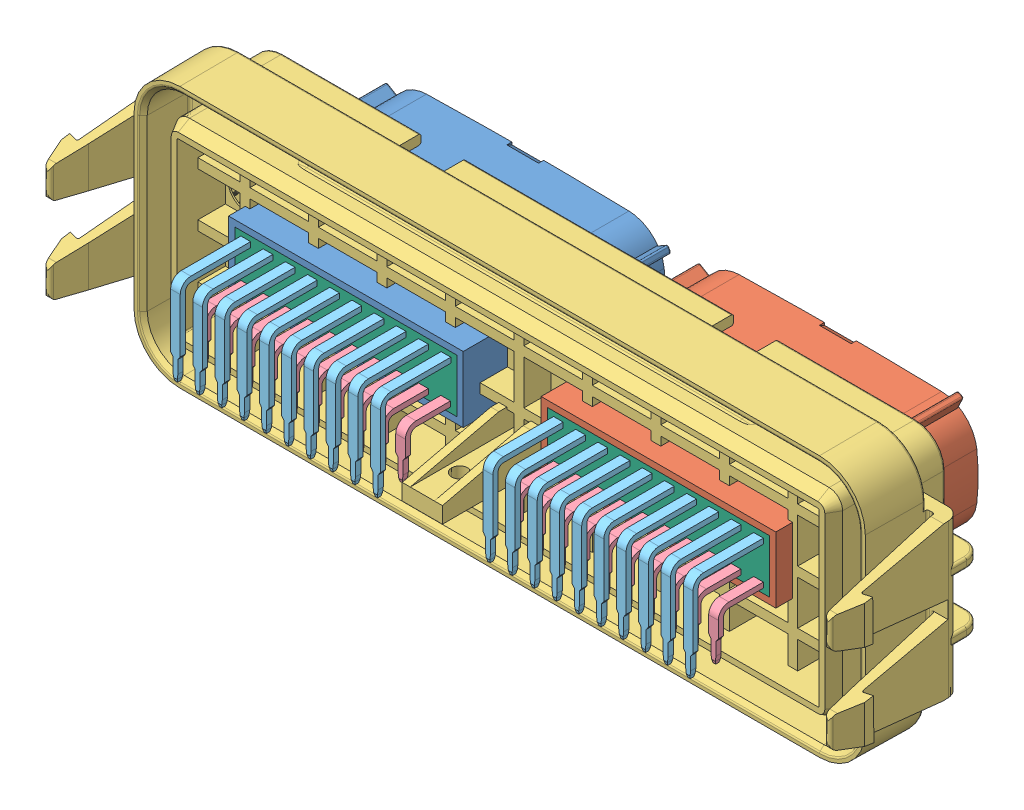
SolidWorks assembly 5810140011_model, configuration Default. Lengths in mm.
Overall size (126.6 41.34 41.26).
49 component instances, 6 part files, 0 mates.
Components (placement in the parent):
- 5810140011_model.stp-1: 5810140011_model.stp [Default] at origin size (126.6 41.34 41.26)
  - 4828770271-ME-MX-L20B-R20A_ASM.stp-1: 4828770271-ME-MX-L20B-R20A_ASM.stp [Default] at (0 -1.143 0) x (-1 0 0) z (0 0 -1) size (126.6 41.34 41.26)
    - MOLEX-ME-A-20W_AF2_ASM.stp-1: MOLEX-ME-A-20W_AF2_ASM.stp [Default] at (24.638 1.143 0) size (47 22 28.67)
      - MOLEX-ME-A-20W_AF3.stp-1: MOLEX-ME-A-20W_AF3.stp [Default] at (-17.9886 -11.4851 -14.215) size (47 22 28.67)
    - MOLEX-ME-B-20W_AF2_ASM.stp-1: MOLEX-ME-B-20W_AF2_ASM.stp [Default] at (-24.638 1.143 0) size (47 22 28.67)
      - MOLEX-ME-B-20W_AF3.stp-1: MOLEX-ME-B-20W_AF3.stp [Default] at (-17.9886 -11.4851 -14.215) size (47 22 28.67)
    - 4741170136_MX_ME_L20B-R20A_AF1.stp-1: 4741170136_MX_ME_L20B-R20A_AF1.stp [Default] at origin size (126.6 41.34 27.94)
  - 4040011260_TYPE4.stp-1: 4040011260_TYPE4.stp [Default] at (40.4134 -3.0216 -10.4678) x (-1 0 0) z (0 0 1) size (2.54 8.02 26.57)
  - 4040011261_TYPE5.stp-1: 4040011261_TYPE5.stp [Default] at (40.4134 2.9784 -10.4678) x (-1 0 0) z (0 0 1) size (2.54 14.02 30.56)
  - 4040011260_TYPE4.stp-2: 4040011260_TYPE4.stp [Default] at (8.8626 -3.0216 -10.4678) x (-1 0 0) z (0 0 1) size (2.54 8.02 26.57)
  - 4040011261_TYPE5.stp-2: 4040011261_TYPE5.stp [Default] at (8.8626 3.0419 -10.4678) x (-1 0 0) z (0 0 1) size (2.54 14.02 30.56)
  - 4040011260_TYPE4.stp-3: 4040011260_TYPE4.stp [Default] at (-40.4134 -3.0216 -10.4678) x (-1 0 0) z (0 0 1) size (2.54 8.02 26.57)
  - 4040011261_TYPE5.stp-3: 4040011261_TYPE5.stp [Default] at (-40.4134 3.0419 -10.4678) x (-1 0 0) z (0 0 1) size (2.54 14.02 30.56)
  - 4040011260_TYPE4.stp-4: 4040011260_TYPE4.stp [Default] at (-8.9134 -2.9581 -10.4678) x (-1 0 0) z (0 0 1) size (2.54 8.02 26.57)
  - 4040011261_TYPE5.stp-4: 4040011261_TYPE5.stp [Default] at (-8.8626 3.0419 -10.4678) x (-1 0 0) z (0 0 1) size (2.54 14.02 30.56)
  - 4040011260_TYPE4.stp-5: 4040011260_TYPE4.stp [Default] at (36.8626 -3.0216 -10.4678) x (-1 0 0) z (0 0 1) size (2.54 8.02 26.57)
  - 4040011260_TYPE4.stp-6: 4040011260_TYPE4.stp [Default] at (33.3626 -3.0216 -10.4678) x (-1 0 0) z (0 0 1) size (2.54 8.02 26.57)
  - 4040011260_TYPE4.stp-7: 4040011260_TYPE4.stp [Default] at (29.8626 -3.0216 -10.4678) x (-1 0 0) z (0 0 1) size (2.54 8.02 26.57)
  - 4040011260_TYPE4.stp-8: 4040011260_TYPE4.stp [Default] at (26.3626 -3.0216 -10.4678) x (-1 0 0) z (0 0 1) size (2.54 8.02 26.57)
  - 4040011260_TYPE4.stp-9: 4040011260_TYPE4.stp [Default] at (22.8626 -3.0216 -10.4678) x (-1 0 0) z (0 0 1) size (2.54 8.02 26.57)
  - 4040011260_TYPE4.stp-10: 4040011260_TYPE4.stp [Default] at (19.3626 -3.0216 -10.4678) x (-1 0 0) z (0 0 1) size (2.54 8.02 26.57)
  - 4040011260_TYPE4.stp-11: 4040011260_TYPE4.stp [Default] at (15.8626 -3.0216 -10.4678) x (-1 0 0) z (0 0 1) size (2.54 8.02 26.57)
  - 4040011260_TYPE4.stp-12: 4040011260_TYPE4.stp [Default] at (12.3626 -3.0216 -10.4678) x (-1 0 0) z (0 0 1) size (2.54 8.02 26.57)
  - 4040011260_TYPE4.stp-13: 4040011260_TYPE4.stp [Default] at (-12.4134 -3.0216 -10.4678) x (-1 0 0) z (0 0 1) size (2.54 8.02 26.57)
  - 4040011260_TYPE4.stp-14: 4040011260_TYPE4.stp [Default] at (-15.9134 -3.0216 -10.4678) x (-1 0 0) z (0 0 1) size (2.54 8.02 26.57)
  - 4040011260_TYPE4.stp-15: 4040011260_TYPE4.stp [Default] at (-19.4134 -3.0216 -10.4678) x (-1 0 0) z (0 0 1) size (2.54 8.02 26.57)
  - 4040011260_TYPE4.stp-16: 4040011260_TYPE4.stp [Default] at (-22.9134 -3.0216 -10.4678) x (-1 0 0) z (0 0 1) size (2.54 8.02 26.57)
  - 4040011260_TYPE4.stp-17: 4040011260_TYPE4.stp [Default] at (-26.4134 -3.0216 -10.4678) x (-1 0 0) z (0 0 1) size (2.54 8.02 26.57)
  - 4040011260_TYPE4.stp-18: 4040011260_TYPE4.stp [Default] at (-29.9134 -3.0216 -10.4678) x (-1 0 0) z (0 0 1) size (2.54 8.02 26.57)
  - 4040011260_TYPE4.stp-19: 4040011260_TYPE4.stp [Default] at (-33.4134 -3.0216 -10.4678) x (-1 0 0) z (0 0 1) size (2.54 8.02 26.57)
  - 4040011260_TYPE4.stp-20: 4040011260_TYPE4.stp [Default] at (-36.9134 -3.0216 -10.4678) x (-1 0 0) z (0 0 1) size (2.54 8.02 26.57)
  - 4040011261_TYPE5.stp-5: 4040011261_TYPE5.stp [Default] at (36.8626 3.0419 -10.4678) x (-1 0 0) z (0 0 1) size (2.54 14.02 30.56)
  - 4040011261_TYPE5.stp-6: 4040011261_TYPE5.stp [Default] at (33.3626 3.0419 -10.4678) x (-1 0 0) z (0 0 1) size (2.54 14.02 30.56)
  - 4040011261_TYPE5.stp-7: 4040011261_TYPE5.stp [Default] at (29.8626 3.0419 -10.4678) x (-1 0 0) z (0 0 1) size (2.54 14.02 30.56)
  - 4040011261_TYPE5.stp-8: 4040011261_TYPE5.stp [Default] at (26.3626 3.0419 -10.4678) x (-1 0 0) z (0 0 1) size (2.54 14.02 30.56)
  - 4040011261_TYPE5.stp-9: 4040011261_TYPE5.stp [Default] at (22.8626 3.0419 -10.4678) x (-1 0 0) z (0 0 1) size (2.54 14.02 30.56)
  - 4040011261_TYPE5.stp-10: 4040011261_TYPE5.stp [Default] at (19.3626 3.0419 -10.4678) x (-1 0 0) z (0 0 1) size (2.54 14.02 30.56)
  - 4040011261_TYPE5.stp-11: 4040011261_TYPE5.stp [Default] at (15.8626 3.0419 -10.4678) x (-1 0 0) z (0 0 1) size (2.54 14.02 30.56)
  - 4040011261_TYPE5.stp-12: 4040011261_TYPE5.stp [Default] at (12.3626 3.0419 -10.4678) x (-1 0 0) z (0 0 1) size (2.54 14.02 30.56)
  - 4040011261_TYPE5.stp-13: 4040011261_TYPE5.stp [Default] at (-12.4134 3.0419 -10.4678) x (-1 0 0) z (0 0 1) size (2.54 14.02 30.56)
  - 4040011261_TYPE5.stp-14: 4040011261_TYPE5.stp [Default] at (-15.9134 3.0419 -10.4678) x (-1 0 0) z (0 0 1) size (2.54 14.02 30.56)
  - 4040011261_TYPE5.stp-15: 4040011261_TYPE5.stp [Default] at (-19.4134 3.0419 -10.4678) x (-1 0 0) z (0 0 1) size (2.54 14.02 30.56)
  - 4040011261_TYPE5.stp-16: 4040011261_TYPE5.stp [Default] at (-22.9134 3.0419 -10.4678) x (-1 0 0) z (0 0 1) size (2.54 14.02 30.56)
  - 4040011261_TYPE5.stp-17: 4040011261_TYPE5.stp [Default] at (-26.4134 3.0419 -10.4678) x (-1 0 0) z (0 0 1) size (2.54 14.02 30.56)
  - 4040011261_TYPE5.stp-18: 4040011261_TYPE5.stp [Default] at (-29.9134 3.0419 -10.4678) x (-1 0 0) z (0 0 1) size (2.54 14.02 30.56)
  - 4040011261_TYPE5.stp-19: 4040011261_TYPE5.stp [Default] at (-33.4134 3.0419 -10.4678) x (-1 0 0) z (0 0 1) size (2.54 14.02 30.56)
  - 4040011261_TYPE5.stp-20: 4040011261_TYPE5.stp [Default] at (-36.9134 3.0419 -10.4678) x (-1 0 0) z (0 0 1) size (2.54 14.02 30.56)
  - ME-MX-20W-POTTING.stp-1: ME-MX-20W-POTTING.stp [Default] at (24.638 0 9) x (1 0 0) z (0 -1 0) size (35 6.97 8.4)
  - ME-MX-20W-POTTING.stp-2: ME-MX-20W-POTTING.stp [Default] at (-24.638 0 9) x (1 0 0) z (0 -1 0) size (35 6.97 8.4)
